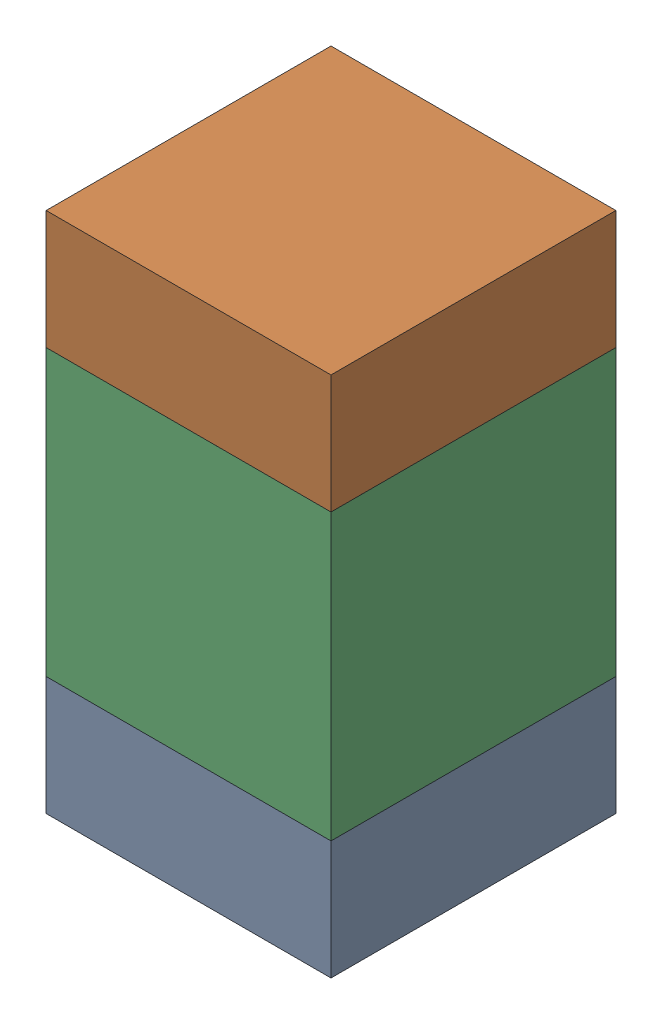
SolidWorks assembly C410PCB, configuration Default. Lengths in mm.
Overall size (0.6 1.1 0.6).
6 component instances, 2 part files, 0 mates.
Components (placement in the parent):
- 854785296-1: 854785296 [Default] at (85.69 89.275 0) size (0.6 0.25 0.6)
  - Extruded_10-1: Extruded_10 [Default] at origin size (0.6 0.25 0.6)
- 854785296-2: 854785296 [Default] at (85.69 90.125 0) size (0.6 0.25 0.6)
  - Extruded_10-1: Extruded_10 [Default] at origin size (0.6 0.25 0.6)
- 761606048-1: 761606048 [Default] at (85.69 89.7 0) size (0.6 0.6 0.6)
  - Extruded_9-1: Extruded_9 [Default] at origin size (0.6 0.6 0.6)
